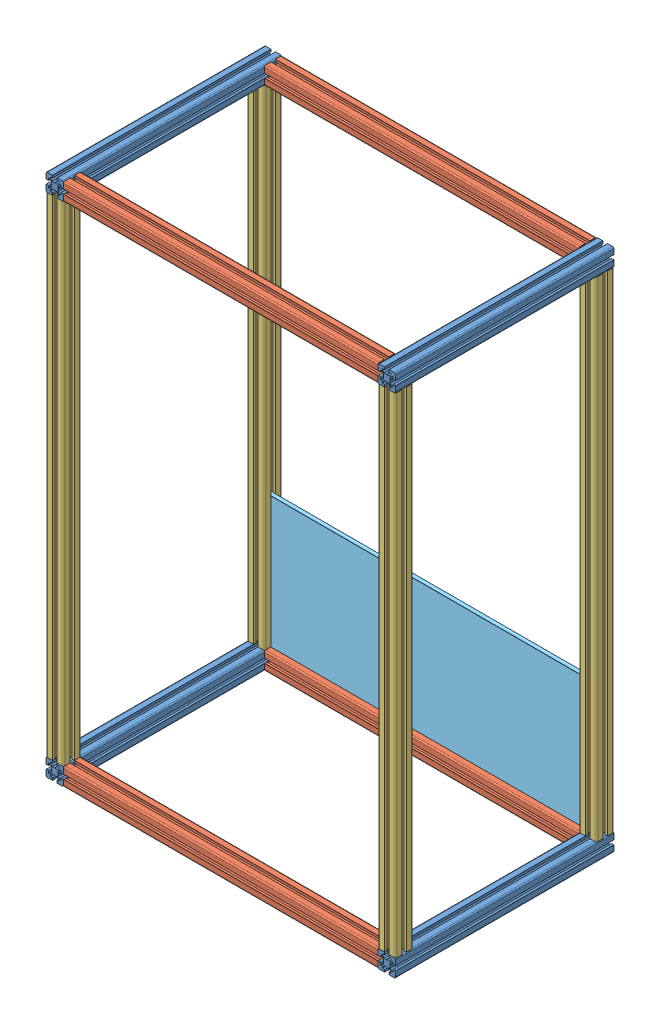
SolidWorks assembly CarBody_Caster, configuration ﾃﾞﾌｫﾙﾄ. Lengths in mm.
Overall size (800 1200 628.23).
14 component instances, 5 part files, 13 mates.
Components (placement in the parent):
- Flame_500mm-1: Flame_500mm [ﾃﾞﾌｫﾙﾄ] at origin size (40 40 500)
- Flame_500mm-2: Flame_500mm [ﾃﾞﾌｫﾙﾄ] at (760 0 0) size (40 40 500)
- Flame_720mm-1: Flame_720mm [ﾃﾞﾌｫﾙﾄ] at (70 100 30) x (0 0 -1) z (-1 0 0) size (40 40 720)
- Flame_720mm-2: Flame_720mm [ﾃﾞﾌｫﾙﾄ] at (790 0 -430) x (0 0 -1) z (1 0 0) size (40 40 720)
- Flame_1120mm-1: Flame_1120mm [ﾃﾞﾌｫﾙﾄ] at (100 70 -70) x (0 0 1) z (0 -1 0) size (40 40 1120)
- Flame_1120mm-2: Flame_1120mm [ﾃﾞﾌｫﾙﾄ] at (0 70 -530) x (1 0 0) z (0 -1 0) size (40 40 1120)
- Flame_1120mm-3: Flame_1120mm [ﾃﾞﾌｫﾙﾄ] at (760 70 -530) x (1 0 0) z (0 -1 0) size (40 40 1120)
- Flame_1120mm-4: Flame_1120mm [ﾃﾞﾌｫﾙﾄ] at (760 70 -70) x (1 0 0) z (0 -1 0) size (40 40 1120)
- Flame_500mm-3: Flame_500mm [ﾃﾞﾌｫﾙﾄ] at (0 1160 0) size (40 40 500)
- Flame_500mm-4: Flame_500mm [ﾃﾞﾌｫﾙﾄ] at (760 1160 0) size (40 40 500)
- Flame_720mm-3: Flame_720mm [ﾃﾞﾌｫﾙﾄ] at (790 1160 -430) x (0 0 -1) z (1 0 0) size (40 40 720)
- Flame_720mm-4: Flame_720mm [ﾃﾞﾌｫﾙﾄ] at (790 1160 30) x (0 0 -1) z (1 0 0) size (40 40 720)
- pms_100uwb_Caster-1: pms_100uwb_Caster [ﾃﾞﾌｫﾙﾄ] at (443.6345 135.9332 -484.2304) x (0 1 0) z (1 0 0) size (129.5 144 95)
- CasterBasePlate_5052P-1: CasterBasePlate_5052P [Default] at (749.917 352.4713 -484.2304) size (732.5 300 9.5)
Mates (geometry in assembly coordinates):
- 一致1: coincident aligned: line of Flame_500mm-1 through (11.7 70 67) axis (0 0 -1); line of Flame_720mm-1 through (70 67 0) axis (0 -1 0)
- 一致2: coincident: point of Flame_500mm-2; unknown of Flame_720mm-1
- 一致3: coincident: unknown of Flame_500mm-1; unknown of Flame_720mm-2
- 一致4: coincident: unknown of Flame_500mm-1; unknown of Flame_1120mm-1
- 一致6: coincident: unknown of Flame_500mm-1; unknown of Flame_1120mm-2
- 一致7: coincident: unknown of Flame_500mm-2; unknown of Flame_1120mm-3
- 一致8: coincident: unknown of Flame_500mm-2; unknown of Flame_1120mm-4
- 一致10: coincident: unknown of Flame_1120mm-2; unknown of Flame_500mm-3
- 一致11: coincident: unknown of Flame_1120mm-4; unknown of Flame_500mm-4
- 一致14: coincident: unknown of Flame_500mm-4; unknown of Flame_720mm-4
- 一致16: coincident: unknown of Flame_500mm-4; unknown of Flame_720mm-3
- 一致18: coincident: unknown of Flame_1120mm-2; unknown of CasterBasePlate_5052P-1
- 一致25: coincident anti-aligned: plane of pms_100uwb_Caster-1 through (480.6345 172.9332 -484.2304) normal (0 0 1); plane of CasterBasePlate_5052P-1 through (749.917 352.4713 -484.2304) normal (0 0 -1)
